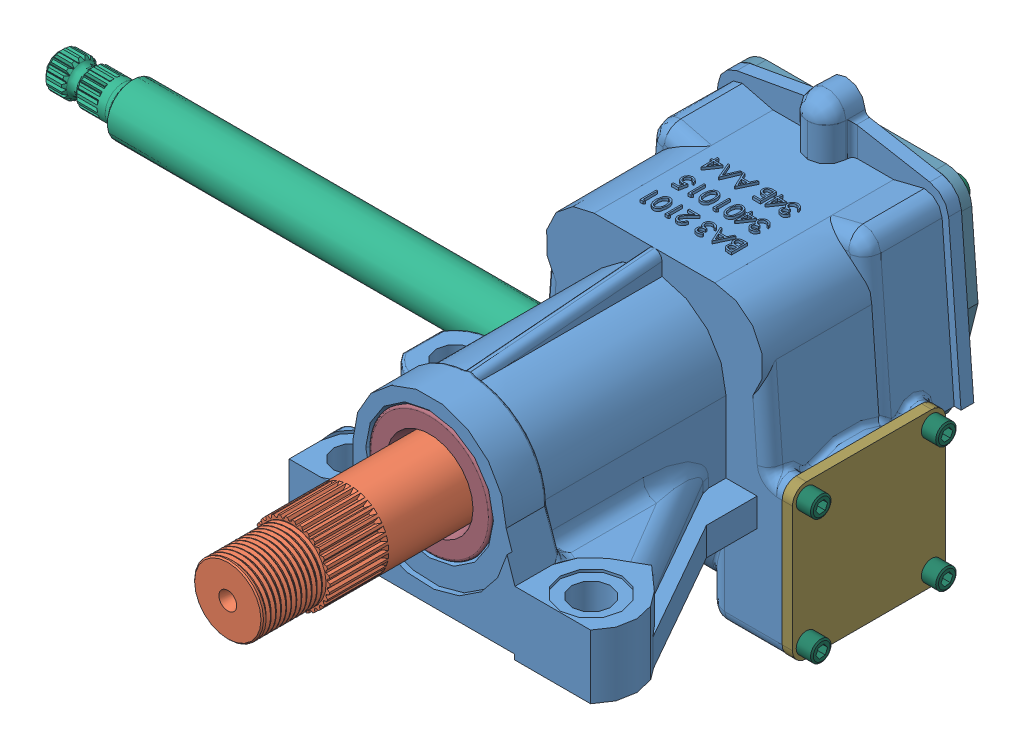
SolidWorks assembly Общая сборка, configuration По умолчанию. Lengths in mm.
Overall size (333.42 142.34 256.63).
51 component instances, 16 part files, 26 mates.
Components (placement in the parent):
- корпус рулевого режуктора-1: корпус рулевого режуктора [Default] at origin size (136.26 136.5 165)
- подсборка вала-2: подсборка вала [По умолчанию] at (-113.315 -142.2512 -23.0381) size (64.74 65 256.63)
  - вал-1: вал [По умолчанию] at (113.315 142.2512 142.0381) size (64.74 60.51 231)
  - штивт для вала-1: штивт для вала [По умолчанию] at (136.8301 118.7512 71.8381) x (0.04 0.979796 -0.195959) z (-0.195959 0.2 0.96) size (13 48 13)
  - ролик для вала-1: ролик для вала [По умолчанию] at (106.8687 118.7512 65.7223) x (0.979796 0 0.2) z (-0.2 0 0.979796) size (29 33 33)
  - резьба под вал-1: резьба под вал [По умолчанию] at (113.315 147.4612 9.0381) x (0 0 1) z (1 0 0) size (31.63 22 22)
- подсборка червячного вала-1: подсборка червячного вала [По умолчанию] at (-63.1614 -48.9674 45) x (0 -0.997241 -0.074235) z (-1 0 0) size (68.76 68.76 311.16)
  - вал с червяком-1: вал с червяком [Default] at origin size (50.58 50.33 303.38)
  - подсборка подшипника-1: подсборка подшипника [По умолчанию] at (0 0 -94.0739) x (0 0 1) z (0.836092 -0.54859 0) size (10 40 40)
    - обойма подшипника 2-1: обойма подшипника 2 [По умолчанию] at origin size (10 40 40)
    - шарик подшипника-1: шарик подшипника [По умолчанию] at (-3.4256 15 0) size (8 8 8)
    - шарик подшипника-2: шарик подшипника [По умолчанию] at (-3.4256 12.9904 -7.5) x (1 0 0) z (0 0.5 0.866025) size (8 8 8)
    - шарик подшипника-3: шарик подшипника [По умолчанию] at (-3.4256 7.5 -12.9904) x (1 0 0) z (0 0.866025 0.5) size (8 8 8)
    - шарик подшипника-4: шарик подшипника [По умолчанию] at (-3.4256 0 -15) x (1 0 0) z (0 1 0) size (8 8 8)
    - шарик подшипника-5: шарик подшипника [По умолчанию] at (-3.4256 -7.5 -12.9904) x (1 0 0) z (0 0.866025 -0.5) size (8 8 8)
    - шарик подшипника-6: шарик подшипника [По умолчанию] at (-3.4256 -12.9904 -7.5) x (1 0 0) z (0 0.5 -0.866025) size (8 8 8)
    - шарик подшипника-7: шарик подшипника [По умолчанию] at (-3.4256 -15 0) x (1 0 0) z (0 0 -1) size (8 8 8)
    - шарик подшипника-8: шарик подшипника [По умолчанию] at (-3.4256 -12.9904 7.5) x (1 0 0) z (0 -0.5 -0.866025) size (8 8 8)
    - шарик подшипника-9: шарик подшипника [По умолчанию] at (-3.4256 -7.5 12.9904) x (1 0 0) z (0 -0.866025 -0.5) size (8 8 8)
    - шарик подшипника-10: шарик подшипника [По умолчанию] at (-3.4256 0 15) x (1 0 0) z (0 -1 0) size (8 8 8)
    - шарик подшипника-11: шарик подшипника [По умолчанию] at (-3.4256 7.5 12.9904) x (1 0 0) z (0 -0.866025 0.5) size (8 8 8)
    - шарик подшипника-12: шарик подшипника [По умолчанию] at (-3.4256 12.9904 7.5) x (1 0 0) z (0 -0.5 0.866025) size (8 8 8)
  - подсборка подшипника-2: подсборка подшипника [По умолчанию] at (0 0 -33.2438) x (0 0 -1) z (-0.946737 -0.322007 0) size (10 40 40)
    - обойма подшипника 2-1: обойма подшипника 2 [По умолчанию] at origin size (10 40 40)
    - шарик подшипника-1: шарик подшипника [По умолчанию] at (-3.4256 15 0) size (8 8 8)
    - шарик подшипника-2: шарик подшипника [По умолчанию] at (-3.4256 12.9904 -7.5) x (1 0 0) z (0 0.5 0.866025) size (8 8 8)
    - шарик подшипника-3: шарик подшипника [По умолчанию] at (-3.4256 7.5 -12.9904) x (1 0 0) z (0 0.866025 0.5) size (8 8 8)
    - шарик подшипника-4: шарик подшипника [По умолчанию] at (-3.4256 0 -15) x (1 0 0) z (0 1 0) size (8 8 8)
    - шарик подшипника-5: шарик подшипника [По умолчанию] at (-3.4256 -7.5 -12.9904) x (1 0 0) z (0 0.866025 -0.5) size (8 8 8)
    - шарик подшипника-6: шарик подшипника [По умолчанию] at (-3.4256 -12.9904 -7.5) x (1 0 0) z (0 0.5 -0.866025) size (8 8 8)
    - шарик подшипника-7: шарик подшипника [По умолчанию] at (-3.4256 -15 0) x (1 0 0) z (0 0 -1) size (8 8 8)
    - шарик подшипника-8: шарик подшипника [По умолчанию] at (-3.4256 -12.9904 7.5) x (1 0 0) z (0 -0.5 -0.866025) size (8 8 8)
    - шарик подшипника-9: шарик подшипника [По умолчанию] at (-3.4256 -7.5 12.9904) x (1 0 0) z (0 -0.866025 -0.5) size (8 8 8)
    - шарик подшипника-10: шарик подшипника [По умолчанию] at (-3.4256 0 15) x (1 0 0) z (0 -1 0) size (8 8 8)
    - шарик подшипника-11: шарик подшипника [По умолчанию] at (-3.4256 7.5 12.9904) x (1 0 0) z (0 -0.866025 0.5) size (8 8 8)
    - шарик подшипника-12: шарик подшипника [По умолчанию] at (-3.4256 12.9904 7.5) x (1 0 0) z (0 -0.5 0.866025) size (8 8 8)
  - вторая часть подшипника-2: вторая часть подшипника [По умолчанию] at (0 0 -21.6786) x (0 0 -1) z (0.522753 0.852484 0) size (16 50 50)
  - вторая часть подшипника (меньшая)-1: вторая часть подшипника (меньшая) [По умолчанию] at (3.4387 3.2133 -107.9824) x (0 0 1) z (0.682748 -0.730654 0) size (16 45 45)
- сальльник-1: сальльник [По умолчанию] at (-57.5076 -48.9674 45) x (1 0 0) z (0 -0.140599 0.990067) size (9 35 35)
- боковая крышка-2: боковая крышка [По умолчанию] at (54 -48.9674 45) x (0 1 0) z (0 0 1) size (60 4 60)
- сальник-2: сальник [По умолчанию] at (0 33.3706 110.8673) size (48 48 9)
- лобовая крышка-3: лобовая крышка [По умолчанию] at (-20.1101 47.1958 0) x (-1 0 0) z (0 0 -1) size (95.29 87.68 9)
- socket set screw cone point_iso-1: socket set screw cone point_iso [ISO 4027 - M8 x 10-N] at (60 -24.4674 69.5) x (-1 0 0) z (0 -0.912093 0.409983) size (10 8 8)
- socket set screw cone point_iso-3: socket set screw cone point_iso [ISO 4027 - M8 x 10-N] at (60 -24.4674 20.5) x (-1 0 0) z (0 -0.912093 0.409983) size (10 8 8)
- socket set screw cone point_iso-4: socket set screw cone point_iso [ISO 4027 - M8 x 10-N] at (60 -73.4674 20.5) x (-1 0 0) z (0 -0.912093 0.409983) size (10 8 8)
- socket set screw cone point_iso-5: socket set screw cone point_iso [ISO 4027 - M8 x 10-N] at (60 -73.4674 69.5) x (-1 0 0) z (0 -0.912093 0.409983) size (10 8 8)
- socket set screw cone point_iso-15: socket set screw cone point_iso [ISO 4027 - M8 x 8-N] at (-35.238 32.5546 -9.6906) x (0 0 1) z (-0.998776 -0.049462 0) size (8 8 8)
- socket set screw cone point_iso-17: socket set screw cone point_iso [ISO 4027 - M8 x 8-N] at (35.238 32.5546 -9.6906) x (0 0 1) z (-0.998776 0.049462 0) size (8 8 8)
- socket set screw cone point_iso-18: socket set screw cone point_iso [ISO 4027 - M8 x 8-N] at (28.1922 -34.9674 -10.2679) x (0 0 1) z (0.156207 0.987724 0) size (8 8 8)
- socket set screw cone point_iso-19: socket set screw cone point_iso [ISO 4027 - M8 x 8-N] at (-28.1922 -34.9674 -10.2679) x (0 0 1) z (0.156207 -0.987724 0) size (8 8 8)
- сливная пробка-1: сливная пробка [По умолчанию] at (38.7497 -17.4596 46.7848) x (0 0 1) z (-0.995626 0.093432 0) size (9.3 15.01 13)
Mates (geometry in assembly coordinates):
- Концентричный2: concentric aligned: cylinder of корпус рулевого режуктора-1 through (0 0 -15) axis (0 0 1) radius 15; cylinder of подсборка вала-2/вал-1 through (0 0 69) axis (0 0 1) radius 15
- Совпадение1: coincident anti-aligned: plane of корпус рулевого режуктора-1 through (0 0 69) normal (0 0 -1); plane of подсборка вала-2/вал-1 through (0 0 69) normal (0 0 1)
- Концентричный121: concentric anti-aligned: cylinder of корпус рулевого режуктора-1 through (-55 -48.9674 45) axis (1 0 0) radius 18; cylinder of сальльник-1 through (-99.3311 -48.9674 45) axis (-1 0 0) radius 17.5
- Совпадение61: coincident aligned: plane of корпус рулевого режуктора-1 through (-55 -48.9674 45) normal (-1 0 0); plane of сальльник-1 through (-55 -31.6412 47.4605) normal (-1 0 0)
- Концентричный151: concentric aligned: cylinder of корпус рулевого режуктора-1 through (34 -48.9674 45) axis (1 0 0) radius 25; cylinder of подсборка червячного вала-1/вал с червяком-1 through (-234.1614 -48.9674 45) axis (1 0 0) radius 10
- Совпадение81: coincident anti-aligned: plane of корпус рулевого режуктора-1 through (-47 -48.9674 45) normal (1 0 0); plane of подсборка червячного вала-1/вторая часть подшипника-2 through (-47 -34.3525 24.7169) normal (-1 0 0)
- Совпадение91: coincident anti-aligned: plane of корпус рулевого режуктора-1 through (50 -48.9674 45) normal (1 0 0); plane of боковая крышка-2 through (50 -48.9674 45) normal (-1 0 0)
- Концентричный161: concentric anti-aligned: cylinder of корпус рулевого режуктора-1 through (20 -24.4674 69.5) axis (1 0 0) radius 3; cylinder of боковая крышка-2 through (54 -24.4674 69.5) axis (-1 0 0) radius 4
- Концентричный171: concentric anti-aligned: cylinder of корпус рулевого режуктора-1 through (20 -24.4674 20.5) axis (1 0 0) radius 3; cylinder of боковая крышка-2 through (54 -24.4674 20.5) axis (-1 0 0) radius 4
- Концентричный191: concentric aligned: cylinder of корпус рулевого режуктора-1 through (0 0 147) axis (0 0 1) radius 30; cylinder of сальник-2 through (0 0 171.2374) axis (0 0 1) radius 24
- Совпадение101: coincident aligned: plane of корпус рулевого режуктора-1 through (0 0 163) normal (0 0 1); plane of сальник-2 through (0 24 163) normal (0 0 1)
- Совпадение151: coincident aligned: plane of корпус рулевого режуктора-1 through (44.6154 41.0326 5) normal (0.997054 0.076696 0); plane of лобовая крышка-3 through (44.1018 47.7089 -4) normal (0.997054 0.076696 0)
- Совпадение161: coincident aligned: plane of корпус рулевого режуктора-1 through (-44.6154 41.0326 5) normal (-0.997054 0.076696 0); plane of лобовая крышка-3 through (-44.1018 47.7089 -4) normal (-0.997054 0.076696 0)
- Совпадение171: coincident anti-aligned: plane of корпус рулевого режуктора-1 through (0 49.0326 0) normal (0 0 -1); plane of лобовая крышка-3 through (-20.1101 47.1958 0) normal (0 0 1)
- Концентричный341: concentric aligned: cylinder of корпус рулевого режуктора-1 through (-35.238 32.5546 26) axis (0 0 -1) radius 3; cylinder of лобовая крышка-3 through (-35.238 32.5546 0) axis (0 0 -1) radius 3
- Концентричный73: concentric aligned: cylinder of корпус рулевого режуктора-1 through (20 -24.4674 69.5) axis (1 0 0) radius 3; cylinder of socket set screw cone point_iso-1 through (72.7 -24.4674 69.5) axis (1 0 0) radius 4
- Концентричный78: concentric aligned: cylinder of корпус рулевого режуктора-1 through (-35.238 32.5546 26) axis (0 0 -1) radius 3; cylinder of socket set screw cone point_iso-15 through (-35.238 32.5546 -22.3906) axis (0 0 -1) radius 4
- Концентричный79: concentric aligned: cylinder of лобовая крышка-3 through (-35.238 32.5546 0) axis (0 0 -1) radius 3; cylinder of socket set screw cone point_iso-15 through (-35.238 32.5546 -22.3906) axis (0 0 -1) radius 4
- Совпадение55: coincident aligned: plane of лобовая крышка-3 through (-20.1101 47.1958 -4) normal (0 0 -1); circle of socket set screw cone point_iso-15
- Совпадение56: coincident anti-aligned: circle of боковая крышка-2; circle of socket set screw cone point_iso-1
- Концентричный82: concentric aligned: cylinder of корпус рулевого режуктора-1 through (28.1922 -34.9674 26) axis (0 0 -1) radius 3; cylinder of socket set screw cone point_iso-18 through (28.1922 -34.9674 -22.9679) axis (0 0 -1) radius 4
- Концентричный83: concentric aligned: circle of лобовая крышка-3; cylinder of socket set screw cone point_iso-18 through (28.1922 -34.9674 -22.9679) axis (0 0 -1) radius 4
- Концентричный85: concentric aligned: circle of лобовая крышка-3; circle of socket set screw cone point_iso-18
- Совпадение58: coincident anti-aligned: cone of лобовая крышка-3; cylinder of socket set screw cone point_iso-18 through (28.1922 -34.9674 -4.5774) axis (0 0 1) radius 1047.1976
- Совпадение59: coincident anti-aligned: plane of лобовая крышка-3 through (0 5.2089 -9) normal (0 0 -1); plane of сливная пробка-1 through (11.5749 23.0142 -9) normal (0 0 1)
- Концентричный88: concentric anti-aligned: cylinder of лобовая крышка-3 through (10.8737 15.5415 -5) axis (0 0 -1) radius 6; cylinder of сливная пробка-1 through (10.8737 15.5415 -23.1421) axis (0 0 1) radius 5
